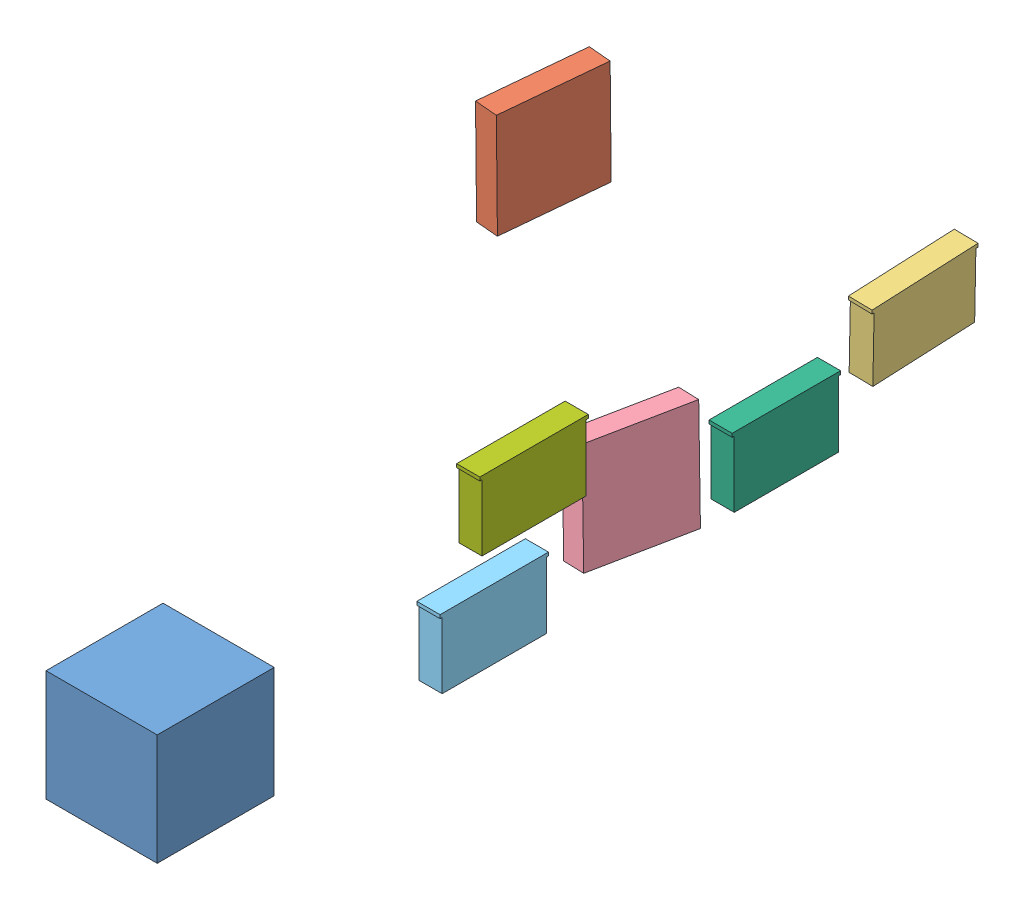
SolidWorks assembly Ensamblaje1, configuration Predeterminado. Lengths in mm.
Overall size (1447.07 1599.85 3836.21).
7 component instances, 7 part files, 0 mates.
Components (placement in the parent):
- Caja 2-2: Caja 2 [Predeterminado] at (-511.9109 -410.7236 -108.2286) size (480 480 505)
- Camino-2: Camino [Predeterminado] at (-887.5291 887.8136 -2092.7943) x (0.095673 0.001361 -0.995412) z (0.995366 0.009553 0.095681) size (487.74 450 299.03)
- Camisa-2: Camisa [Predeterminado] at (-68.9933 288.1035 -2861.5066) x (0.998903 -0.040275 -0.023904) z (0.022993 -0.022933 0.999473) size (419.11 300 1056.57)
- Malla-2: Malla [Predeterminado] at (-545.3588 -230.3986 -2131.5377) x (0.129446 -0.057897 -0.989895) z (0.987845 0.094166 0.12367) size (487.74 450 299.03)
- Manija-2: Manija [Predeterminado] at (125.193 255.4582 -813.2558) size (419.11 307.99 1136.7)
- Parlante-2: Parlante [Predeterminado] at (114.574 292.3319 -2084.5642) size (419.11 300 1056.57)
- Switch-2: Switch [Predeterminado] at (-285.8063 273.0873 -1396.0042) size (419.11 505.47 1236.04)
